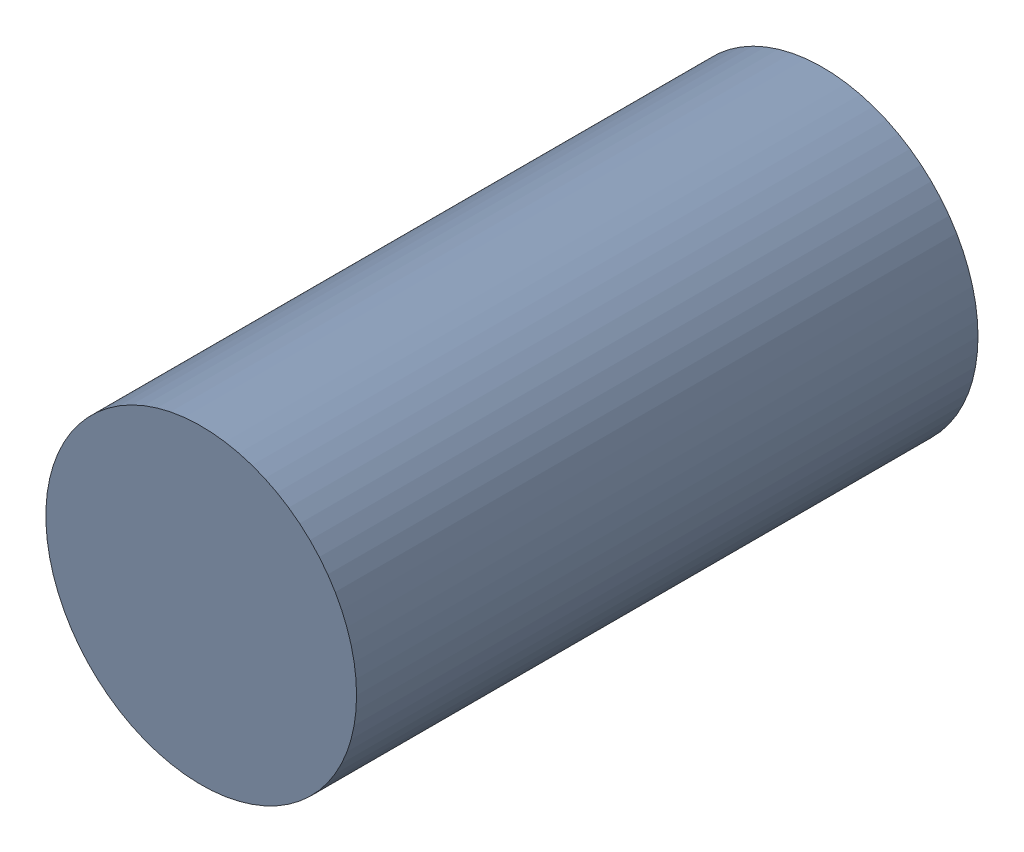
SolidWorks assembly MH13_1.step, configuration Default. Lengths in mm.
Overall size (1 1 2).
2 component instances, 1 part files, 0 mates.
Components (placement in the parent):
- 9228463120_1.step-11: 9228463120_1.step [Default] at (469.2202 311.7064 -1.5) size (1 1 2)
  - Cylinder_1.step-98: Cylinder_1.step [Default] at origin size (1 1 2)
